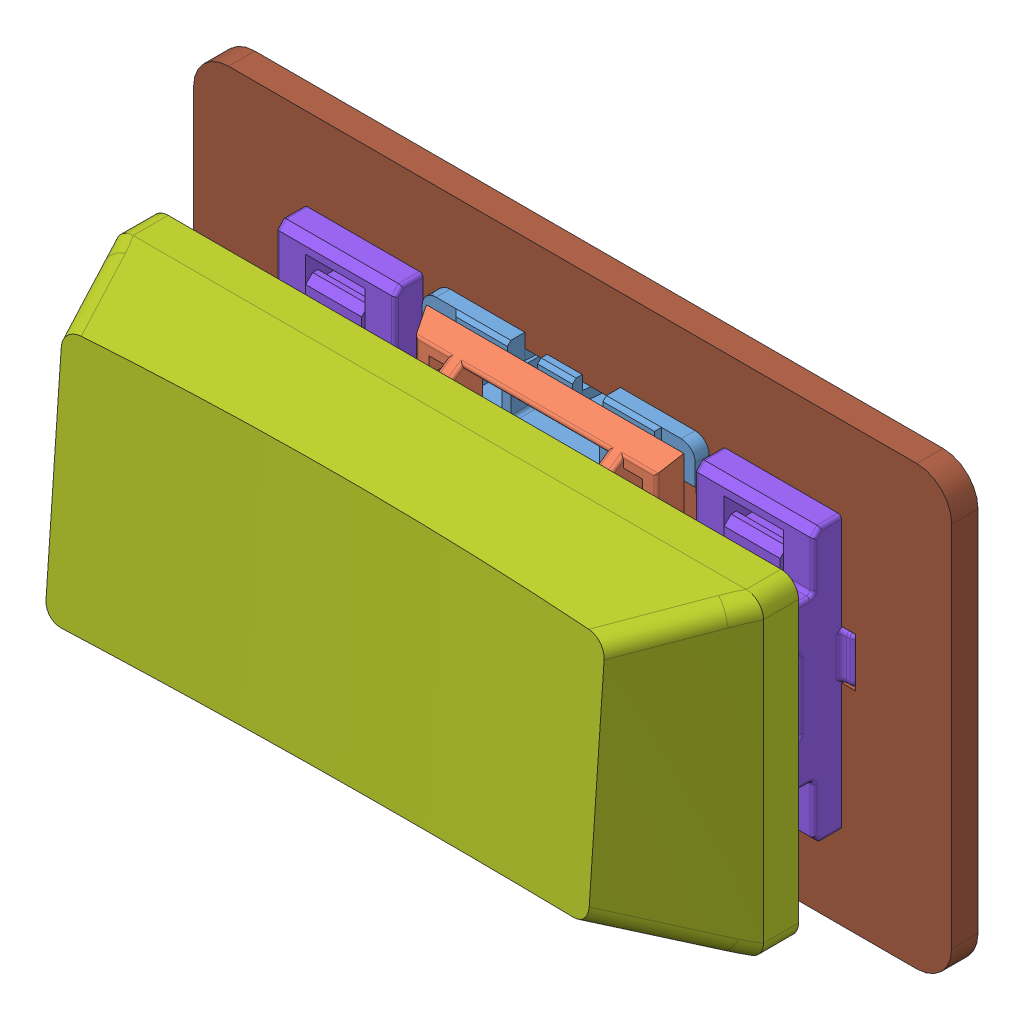
SolidWorks assembly as_stabil_asm.stp, configuration Default. Lengths in mm.
Overall size (43.3 25 23.05).
16 component instances, 11 part files, 0 mates.
Components (placement in the parent):
- AS_ENTER_ASM.stp-1: AS_ENTER_ASM.stp [Default] at (-6.9476 -6.8276 -6.7591) x (0 1 0) z (0 0 -1) size (18.02 37.02 23.05)
  - ASM_MX_ASM.stp-1: ASM_MX_ASM.stp [Default] at (7.4929 7.4929 -8.6575) size (15.6 15.6 18.6)
    - MX_DOWN.stp-1: MX_DOWN.stp [Default] at (0.3071 0.3071 -0.3425) size (15.6 15.6 12.1)
    - MX_UP.stp-1: MX_UP.stp [Default] at (0.3071 0.3071 -5.7425) size (14.71 14.71 9.89)
    - UP_MX.stp-1: UP_MX.stp [Default] at (3.1571 0.3071 0.4575) x (0 1 0) z (-1 0 0) size (8.9 12.4 5.7)
    - MX_PIN.stp-1: MX_PIN.stp [Default] at (-2.5929 4.0071 8.4575) x (0 -1 0) z (1 0 0) size (9.8 13.12 3.74)
    - MX_SPRING.stp-1: MX_SPRING.stp [Default] at (0.3071 0.3071 6.7575) size (3.27 3.27 11.31)
    - MX_CLICK.stp-1: MX_CLICK.stp [Default] at (-2.1462 -4.1429 2.1523) x (1 0 0) z (0 1 0) size (6.85 3.85 8.9)
  - ENTER.stp-1: ENTER.stp [Default] at (7.8 7.8 -13.8) x (0 1 0) z (0 0 -1) size (37.02 18.02 9.25)
- AS_TEST_STABIL_ASM.stp-1: AS_TEST_STABIL_ASM.stp [Default] at (-15.2976 -8.8276 -21.6181) size (32.3 17.6 15.2)
  - STABIL_DOWN_MX.stp-1: STABIL_DOWN_MX.stp [Default] at (4.2 9.8 23.0591) size (8.4 17.6 11.46)
  - STABIL_MX.stp-1: STABIL_MX.stp [Default] at (2 12.625 23.7591) x (0 -1 0) z (-1 0 0) size (8.3 11.95 4.41)
  - STABIL_DOWN_MX.stp-2: STABIL_DOWN_MX.stp [Default] at (28.1 9.8 23.0591) size (8.4 17.6 11.46)
  - STABIL_MX.stp-2: STABIL_MX.stp [Default] at (25.9 12.625 23.7591) x (0 -1 0) z (-1 0 0) size (8.3 11.95 4.41)
  - MX_METAL.stp-1: MX_METAL.stp [Default] at (16.15 11.2814 26.5599) x (1 0 0) z (0 0.587785 -0.809017) size (25.51 12.2 1.68)
- PLATE_STABIL3.stp-1: PLATE_STABIL3.stp [Default] at (0.8524 0.4724 -0.0591) size (43.3 25 1.5)
